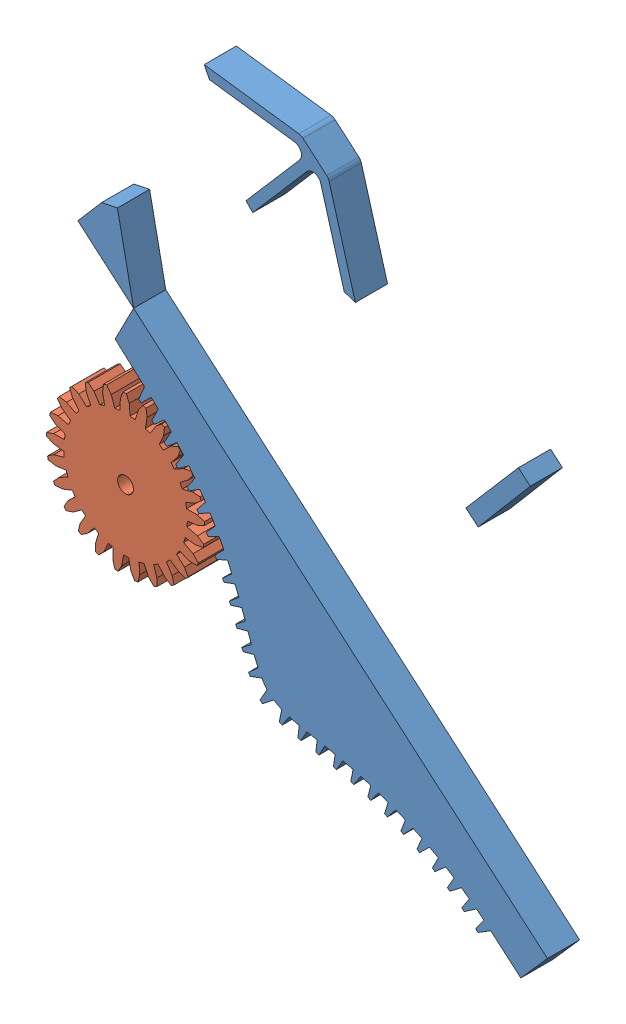
SolidWorks assembly progressive steering, configuration Default. Lengths in mm.
Overall size (166.35 199.69 25.16).
2 component instances, 2 part files, 2 mates.
Components (placement in the parent):
- progressive steering rack-1: progressive steering rack [Default] at (20.9639 133.169 116.748) size (148.19 199.69 10.16)
- elipsed gear-1: elipsed gear [Default] at (-12.9317 -34.4451 126.908) x (-0.416747 -0.909022 0) z (0 0 -1) size (50.1 50.1 25.16)
Mates (geometry in assembly coordinates):
- Coincident2: coincident aligned: plane of progressive steering rack-1 through (20.9639 133.169 116.748) normal (0 0 -1); plane of elipsed gear-1 through (-12.9317 -34.4451 116.748) normal (0 0 -1)
- Tangent2: tangent: circle of assembly; curve of progressive steering rack-1; circle of elipsed gear-1
